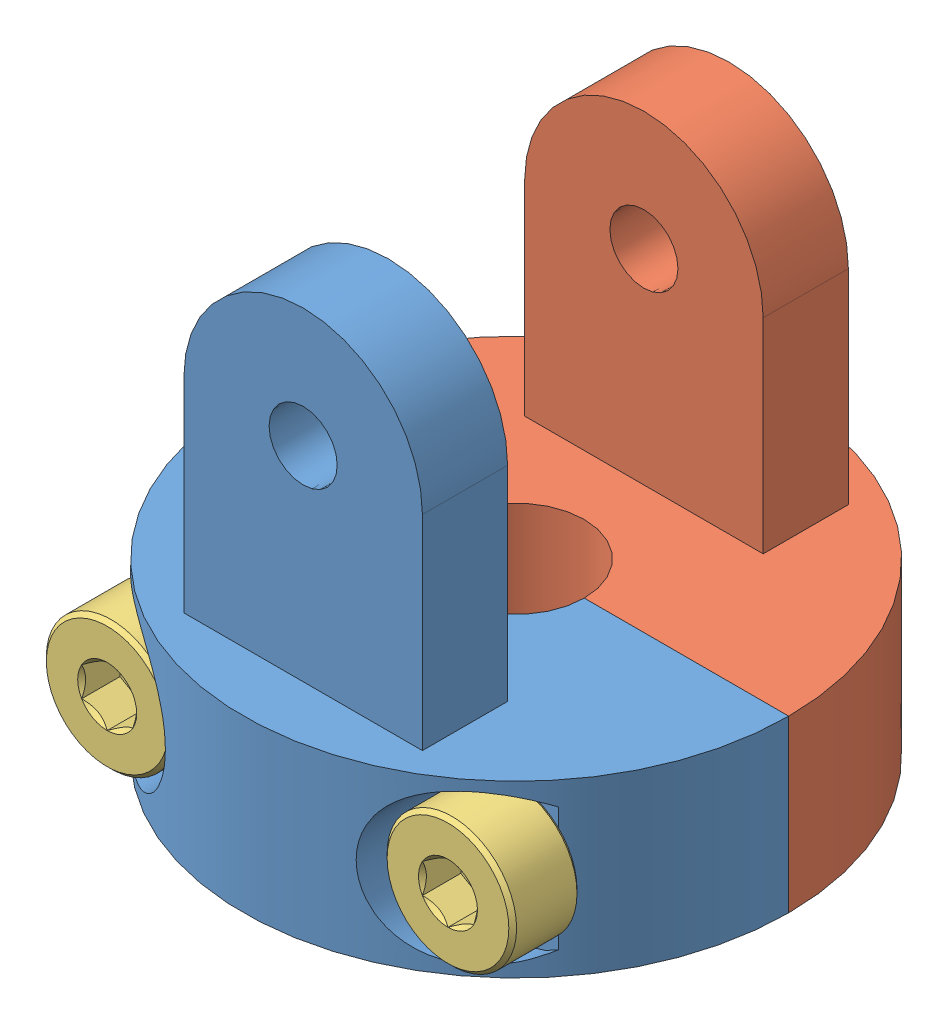
SolidWorks assembly Shaftcoupler, configuration Default. Lengths in mm.
Overall size (16 14.5 16).
4 component instances, 3 part files, 7 mates.
Components (placement in the parent):
- Shaft Coupler - SideA-1: Shaft Coupler - SideA [Default] at (3.5903 3.9792 9.2805) size (16 14.5 8)
- Shaft Coupler - SideB-1: Shaft Coupler - SideB [Default] at (3.5903 3.9792 9.2805) x (-1 0 0) z (0 0 -1) size (16 14.5 8)
- M2 - 10MM - Socket-1: M2 - 10MM - Socket [91290A017] at (8.5903 3.9792 4.2805) x (-1 0 0) z (0 0 -1) size (3.8 3.8 12.12)
- M2 - 10MM - Socket-2: M2 - 10MM - Socket [91290A017] at (-1.4097 3.9792 4.2805) x (-1 0 0) z (0 0 -1) size (3.8 3.8 12.12)
Mates (geometry in assembly coordinates):
- Concentric2: concentric: cylinder of Shaft Coupler - SideA-1 through (-1.4097 3.9792 16.2805) axis (0 0 1) radius 1.2; cylinder of Shaft Coupler - SideB-1 through (-1.4097 3.9792 9.2805) axis (0 0 1) radius 0.8
- Coincident1: coincident: plane of Shaft Coupler - SideA-1 through (1.6303 6.4792 9.2805) normal (0 0 -1); plane of Shaft Coupler - SideB-1 through (1.6303 6.4792 9.2805) normal (0 0 1)
- Concentric7: concentric: cylinder of Shaft Coupler - SideA-1 through (8.5903 3.9792 16.2805) axis (0 0 1) radius 1.2; cylinder of Shaft Coupler - SideB-1 through (8.5903 3.9792 9.2805) axis (0 0 1) radius 0.8
- Coincident2: coincident: plane of Shaft Coupler - SideA-1 through (9.7903 3.9792 14.2805) normal (0 0 1); plane of M2 - 10MM - Socket-1 through (8.5903 3.9792 14.2805) normal (0 0 -1)
- Concentric8: concentric: cylinder of Shaft Coupler - SideA-1 through (8.5903 3.9792 16.2805) axis (0 0 1) radius 1.2; cylinder of M2 - 10MM - Socket-1 through (8.5903 3.9792 16.2805) axis (0 0 -1) radius 1.9
- Coincident3: coincident: plane of Shaft Coupler - SideA-1 through (-0.2097 3.9792 14.2805) normal (0 0 1); plane of M2 - 10MM - Socket-2 through (-1.4097 3.9792 14.2805) normal (0 0 -1)
- Concentric9: concentric: cylinder of Shaft Coupler - SideA-1 through (-1.4097 3.9792 16.2805) axis (0 0 1) radius 1.2; cylinder of M2 - 10MM - Socket-2 through (-1.4097 3.9792 16.2805) axis (0 0 -1) radius 1.9
